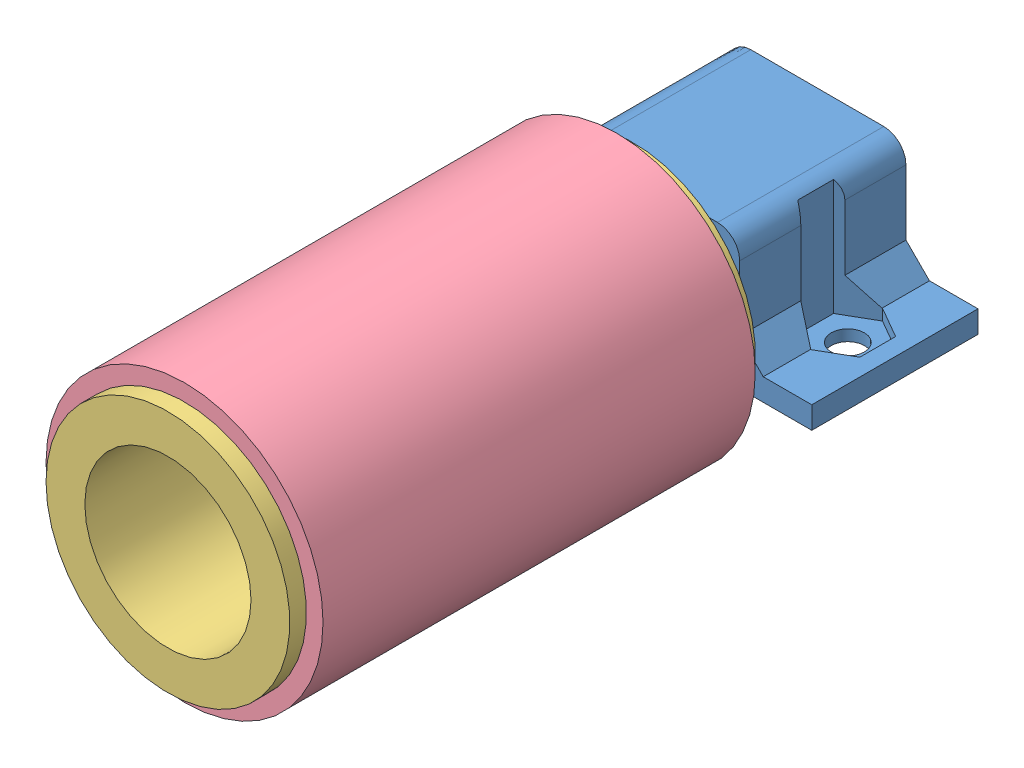
SolidWorks assembly Ensable_motor_pololu, configuration Predeterminado. Lengths in mm.
Overall size (29 25 60.6).
4 component instances, 4 part files, 8 mates.
Components (placement in the parent):
- Bracket_Pololu_Micro_GearMotor_01-1: Bracket_Pololu_Micro_GearMotor_01 [Predeterminado] at (1.8485 -7.5508 29) size (29 12 15)
- Pololu - 1_250 Micro gear motor-1: Pololu - 1_250 Micro gear motor [Default] at (1.8485 -2.5508 29) size (12 10 35.27)
- Wheel_Pololu_GearMotor_42mm-1: Wheel_Pololu_GearMotor_42mm [Predeterminado] at (1.8485 -2.5208 56.1) size (22 22 42)
- Silicone_Wheel_Pololu_GearMotor_42mm-1: Silicone_Wheel_Pololu_GearMotor_42mm [Predeterminado] at (1.8485 -2.5208 78.6) x (1 0 0) z (0 1 0) size (25 39 25)
Mates (geometry in assembly coordinates):
- Coincidente1: coincident anti-aligned: plane of Bracket_Pololu_Micro_GearMotor_01-1 through (5.1651 2.4492 36.5) normal (0 -1 0); plane of Pololu - 1_250 Micro gear motor-1 through (5.1651 2.4492 36.5) normal (0 1 0)
- Concéntrica1: concentric aligned: cylinder of Bracket_Pololu_Micro_GearMotor_01-1 through (1.8485 -2.5508 36.5) axis (0 0 -1) radius 6; cylinder of Pololu - 1_250 Micro gear motor-1 through (1.8485 -2.5508 36.5) axis (0 0 -1) radius 6
- Coincidente2: coincident anti-aligned: plane of Bracket_Pololu_Micro_GearMotor_01-1 through (1.8485 -2.5508 36.5) normal (0 0 1); plane of Pololu - 1_250 Micro gear motor-1 through (-3.1515 -6.5508 36.5) normal (0 0 -1)
- Coincidente4: coincident anti-aligned: plane of Pololu - 1_250 Micro gear motor-1 through (2.8973 -1.5208 43.9567) normal (0 1 0); plane of Wheel_Pololu_GearMotor_42mm-1 through (2.9665 -1.5208 80.1) normal (0 -1 0)
- Coincidente6: coincident anti-aligned: line of Pololu - 1_250 Micro gear motor-1 through (2.8973 -1.5208 46.1) axis (-1 0 0); line of Wheel_Pololu_GearMotor_42mm-1 through (0.7304 -1.5208 46.1) axis (1 0 0)
- Coincidente7: coincident: moEndPointRef_w of Pololu - 1_250 Micro gear motor-1; moEndPointRef_w of Wheel_Pololu_GearMotor_42mm-1
- Concéntrica2: concentric anti-aligned: cylinder of Wheel_Pololu_GearMotor_42mm-1 through (1.8485 -2.5208 56.1) axis (0 0 -1) radius 9.5; cylinder of Silicone_Wheel_Pololu_GearMotor_42mm-1 through (1.8485 -2.5208 39.6) axis (0 0 1) radius 9.5
- Coincidente8: coincident anti-aligned: plane of Wheel_Pololu_GearMotor_42mm-1 through (1.8485 6.9792 39.6) normal (0 0 1); plane of Silicone_Wheel_Pololu_GearMotor_42mm-1 through (1.8485 -2.5208 39.6) normal (0 0 -1)
